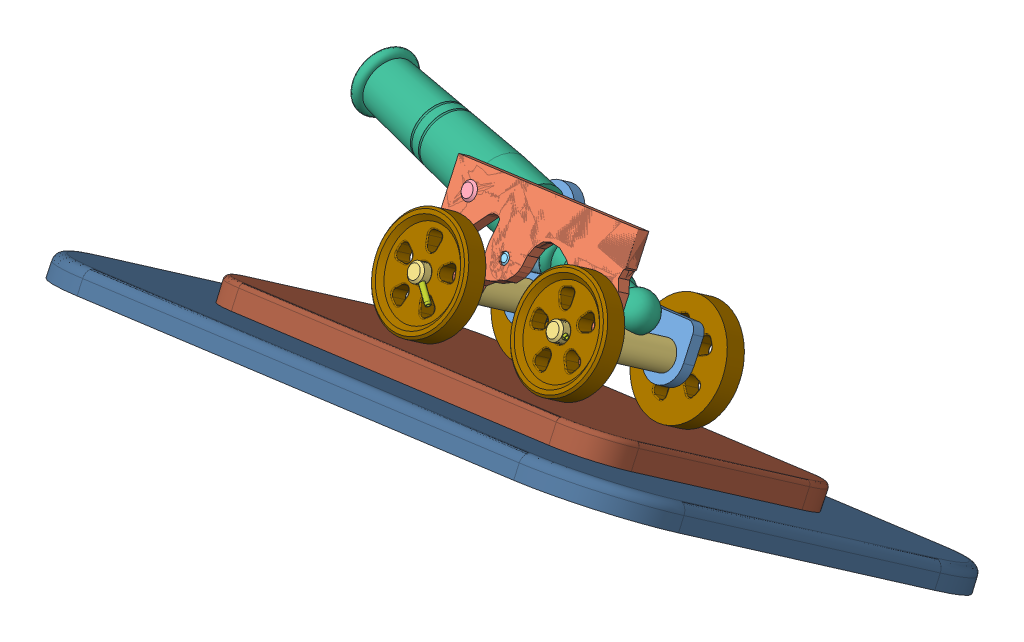
SolidWorks assembly Złożenie1, configuration Domyślna. Lengths in mm.
Overall size (326.22 170.33 191).
18 component instances, 11 part files, 46 mates.
Components (placement in the parent):
- SupportPreMade-1: SupportPreMade [Domyślna] at (-187.0354 39.8991 67.357) x (0.980503 0.186167 0.062894) z (-0.154274 0.531052 0.833177) size (90 50 5.5)
- NewSupport-2: NewSupport [NewSupport] at (-193.0521 60.6102 99.8509) x (0.980503 0.186167 0.062894) z (-0.154274 0.531052 0.833177) size (90.5 50.05 5)
- Axle-1: Axle [Domyślna] at (-176.0562 41.7959 49.5775) x (-0.154274 0.531052 0.833177) z (-0.778757 0.453616 -0.433324) size (70 12 12)
- CannonPin-1: CannonPin [Domyślna] at (-181.5588 72.9675 43.0931) x (-0.154274 0.531052 0.833177) z (0.118877 -0.82717 0.549235) size (46 8.5 8.5)
- SecPin-1: SecPin [Domyślna] at (-155.2532 64.9266 54.2893) x (-0.154274 0.531052 0.833177) z (-0.099202 -0.847337 0.521708) size (44 5 5)
- Axle-2: Axle [Domyślna] at (-107.421 54.8276 53.9801) x (-0.154274 0.531052 0.833177) z (0.987066 0.045635 0.153681) size (70 12 12)
- Barrel-1: Barrel [Domyślna] at (-107.2204 83.0362 78.0454) x (-0.979707 0.026988 -0.198607) z (-0.154274 0.531052 0.833177) size (159.5 26 26)
- spring pin slotted_ai-1: spring pin slotted_ai [SPS 0.0938x0.375] at (-184.286 76.3699 107.032) x (0.778757 -0.453616 0.433324) z (0.47899 -0.016092 -0.877673) size (9.53 2.36 2.36)
- spring pin slotted_ai-2: spring pin slotted_ai [SPS 0.0938x0.375] at (-172.6142 40.8939 53.7903) x (-0.778757 0.453616 -0.433324) z (0.052382 -0.641316 -0.765487) size (9.53 2.36 2.36)
- spring pin slotted_ai-3: spring pin slotted_ai [SPS 0.0938x0.375] at (-112.3569 55.9449 55.3546) x (0.987066 0.045635 0.153681) z (-0.159978 0.218331 0.962673) size (9.53 2.36 2.36)
- spring pin slotted_ai-4: spring pin slotted_ai [SPS 0.0938x0.375] at (-122.3847 90.4632 109.511) x (0.987066 0.045635 0.153681) z (-0.159652 0.366833 0.916485) size (9.53 2.36 2.36)
- WheelBase-1: WheelBase [Domyślna] at (-116.3689 85.6286 102.3043) x (0.925177 0.373607 -0.066821) z (-0.154274 0.531052 0.833177) size (10 10 1)
- Część5^Złożenie1-1: Część5^Złożenie1 [Domyślna] at (-116.5232 86.1597 103.1375) x (0.925177 0.373607 -0.066821) z (-0.154274 0.531052 0.833177) size (44.45 44.45 9) (virtual)
- Część5^Złożenie1-2: Część5^Złożenie1 [Domyślna] at (-109.118 60.6692 63.145) x (-0.886334 -0.447011 0.1208) z (0.154274 -0.531052 -0.833177) size (44.45 44.45 9) (virtual)
- Część5^Złożenie1-3: Część5^Złożenie1 [Domyślna] at (-185.1584 73.1279 98.7349) x (0.397048 -0.738864 0.544457) z (-0.154274 0.531052 0.833177) size (44.45 44.45 9) (virtual)
- Część5^Złożenie1-4: Część5^Złożenie1 [Domyślna] at (-177.7532 47.6374 58.7425) x (-0.838499 0.37567 -0.394705) z (0.154274 -0.531052 -0.833177) size (44.45 44.45 9) (virtual)
- GrassBase-1: GrassBase [Domyślna] at (-146.9015 31.063 103.8247) x (0.980503 0.186167 0.062894) z (-0.154274 0.531052 0.833177) size (300 10 200)
- Część1^Złożenie1-1: Część1^Złożenie1 [Domyślna] at (-148.1186 39.3294 98.3305) x (0.980503 0.186167 0.062894) z (-0.121711 0.826635 -0.549419) size (200 120 10) (virtual)
Mates (geometry in assembly coordinates):
- Koncentryczne1: concentric aligned: cylinder of SupportPreMade-1 through (-178.8331 51.3548 64.5747) axis (0.154274 -0.531052 -0.833177) radius 5.25; cylinder of Axle-1 through (-176.0562 41.7959 49.5775) axis (0.154274 -0.531052 -0.833177) radius 3.95
- Wspólnie1: coincident anti-aligned: plane of SupportPreMade-1 through (-182.4845 76.1539 48.0921) normal (-0.154274 0.531052 0.833177); plane of Axle-1 through (-175.1848 55.649 62.5132) normal (0.154274 -0.531052 -0.833177)
- Koncentryczne2: concentric aligned: cylinder of SupportPreMade-1 through (-156.0245 67.5819 58.4552) axis (0.154274 -0.531052 -0.833177) radius 2.5; cylinder of SecPin-1 through (-155.2532 64.9266 54.2893) axis (0.154274 -0.531052 -0.833177) radius 2.5
- Wspólnie2: coincident aligned: plane of SupportPreMade-1 through (-181.7131 73.4986 43.9262) normal (0.154274 -0.531052 -0.833177); plane of SecPin-1 through (-155.2532 64.9266 54.2893) normal (0.154274 -0.531052 -0.833177)
- Koncentryczne5: concentric aligned: cylinder of SupportPreMade-1 through (-110.1979 64.3865 68.9772) axis (0.154274 -0.531052 -0.833177) radius 5.25; cylinder of Axle-2 through (-107.421 54.8276 53.9801) axis (0.154274 -0.531052 -0.833177) radius 6
- Wspólnie3: coincident anti-aligned: plane of SupportPreMade-1 through (-182.4845 76.1539 48.0921) normal (-0.154274 0.531052 0.833177); plane of Axle-2 through (-110.4595 59.3099 72.1646) normal (0.154274 -0.531052 -0.833177)
- Koncentryczne6: concentric aligned: cylinder of NewSupport-2 through (-116.2146 85.0975 101.4711) axis (0.154274 -0.531052 -0.833177) radius 5.25; cylinder of Axle-2 through (-107.421 54.8276 53.9801) axis (0.154274 -0.531052 -0.833177) radius 6
- Koncentryczne7: concentric aligned: cylinder of NewSupport-2 through (-184.8498 72.0658 97.0686) axis (0.154274 -0.531052 -0.833177) radius 5.25; cylinder of Axle-1 through (-176.0562 41.7959 49.5775) axis (0.154274 -0.531052 -0.833177) radius 6
- Koncentryczne8: concentric aligned: cylinder of NewSupport-2 through (-162.0412 88.2929 90.9491) axis (0.154274 -0.531052 -0.833177) radius 2.5; cylinder of SecPin-1 through (-155.2532 64.9266 54.2893) axis (0.154274 -0.531052 -0.833177) radius 2.5
- Wspólnie4: coincident anti-aligned: plane of NewSupport-2 through (-192.6664 59.2825 97.768) normal (0.154274 -0.531052 -0.833177); plane of Axle-1 through (-181.0382 72.989 91.1848) normal (-0.154274 0.531052 0.833177)
- Wspólnie5: coincident aligned: plane of NewSupport-2 through (-193.4378 61.9378 101.9338) normal (-0.154274 0.531052 0.833177); plane of SecPin-1 through (-162.0412 88.2929 90.9491) normal (-0.154274 0.531052 0.833177)
- Koncentryczne9: concentric aligned: cylinder of SupportPreMade-1 through (-182.4845 76.1539 48.0921) axis (0.154274 -0.531052 -0.833177) radius 3.25; cylinder of CannonPin-1 through (-181.5588 72.9675 43.0931) axis (0.154274 -0.531052 -0.833177) radius 4.25
- Wspólnie6: coincident anti-aligned: plane of NewSupport-2 through (-192.6664 59.2825 97.768) normal (0.154274 -0.531052 -0.833177); plane of CannonPin-1 through (-191.408 93.5205 76.1783) normal (-0.154274 0.531052 0.833177)
- Koncentryczne10: concentric anti-aligned: cylinder of CannonPin-1 through (-181.5588 72.9675 43.0931) axis (0.154274 -0.531052 -0.833177) radius 4.25; cylinder of Barrel-1 through (-183.1016 78.2781 51.4248) axis (-0.154274 0.531052 0.833177) radius 4.25
- Symetrycznie1: symmetric aligned: plane of SupportPreMade-1 through (-181.7131 73.4986 43.9262) normal (0.154274 -0.531052 -0.833177); plane of NewSupport-2 through (-193.4378 61.9378 101.9338) normal (-0.154274 0.531052 0.833177); plane of Barrel-1 through (-107.2204 83.0362 78.0454) normal (-0.154274 0.531052 0.833177)
- Ustalone3: in place: plane of ? through (0 0 9.2378) normal (0 0 1); plane of ? through (0 0 9.2378) normal (0 0 1); moOrthogonalPlaneRef_w of ? through (0 0 9.2378) normal (0 0 1); plane of ? through (0 0 9.2378) normal (0 1 0); plane of ? through (0 0 9.2378) normal (0 0 1); plane of ? through (0 0 9.2378) normal (1 0 0); plane of WheelBase-1 through (-116.5232 86.1597 103.1375) normal (-0.154274 0.531052 0.833177); unknown of Część5^Złożenie1-1
- Wspólnie13: coincident aligned: plane of WheelBase-1; plane of Część5^Złożenie1-1
- Wspólnie14: coincident aligned: moOrthogonalPlaneRef_w of WheelBase-1; plane of Część5^Złożenie1-1 through (-116.5232 86.1597 103.1375) normal (-0.346766 0.760527 -0.548955)
- Wspólnie15: coincident anti-aligned: moOrthogonalPlaneRef_w of WheelBase-1; plane of Część5^Złożenie1-1 through (-116.5232 86.1597 103.1375) normal (0.925177 0.373607 -0.066821)
- Koncentryczne11: concentric aligned: cylinder of Axle-1 through (-176.0562 41.7959 49.5775) axis (0.154274 -0.531052 -0.833177) radius 3.95; cylinder of Część5^Złożenie1-3 through (-186.5468 77.9074 106.2335) axis (0.154274 -0.531052 -0.833177) radius 4
- Odległość1: distance = 2 mm anti-aligned: plane of Część5^Złożenie1-3 through (-185.1584 73.1279 98.7349) normal (0.154274 -0.531052 -0.833177); plane of Axle-1 through (-182.448 74.8928 95.7114) normal (-0.154274 0.531052 0.833177)
- Koncentryczne12: concentric aligned: cylinder of Axle-2 through (-107.421 54.8276 53.9801) axis (0.154274 -0.531052 -0.833177) radius 3.95; cylinder of Część5^Złożenie1-1 through (-117.9116 90.9391 110.6361) axis (0.154274 -0.531052 -0.833177) radius 4
- Odległość2: distance = 2 mm anti-aligned: plane of Axle-2 through (-116.3868 81.7554 103.5695) normal (-0.154274 0.531052 0.833177); plane of Część5^Złożenie1-1 through (-116.5232 86.1597 103.1375) normal (0.154274 -0.531052 -0.833177)
- Koncentryczne14: concentric anti-aligned: cylinder of Axle-2 through (-107.421 54.8276 53.9801) axis (0.154274 -0.531052 -0.833177) radius 3.95; cylinder of Część5^Złożenie1-2 through (-107.7296 55.8897 55.6464) axis (-0.154274 0.531052 0.833177) radius 4
- Koncentryczne15: concentric anti-aligned: cylinder of Axle-1 through (-176.0562 41.7959 49.5775) axis (0.154274 -0.531052 -0.833177) radius 3.95; cylinder of Część5^Złożenie1-4 through (-176.3648 42.858 51.2439) axis (-0.154274 0.531052 0.833177) radius 4
- Odległość3: distance = 2 mm anti-aligned: plane of Część5^Złożenie1-4 through (-177.7532 47.6374 58.7425) normal (-0.154274 0.531052 0.833177); plane of Axle-1 through (-175.0215 52.278 58.6909) normal (0.154274 -0.531052 -0.833177)
- Odległość4: distance = 2 mm anti-aligned: plane of Część5^Złożenie1-2 through (-109.118 60.6692 63.145) normal (-0.154274 0.531052 0.833177); plane of Axle-2 through (-109.6445 57.5007 67.4675) normal (0.154274 -0.531052 -0.833177)
- Koncentryczne16: concentric aligned: cylinder of spring pin slotted_ai-1 through (-191.7037 80.6906 102.9046) axis (-0.778757 0.453616 -0.433324) radius 1.1811; cylinder of Axle-1 through (-181.7972 74.9202 108.4169) axis (-0.778757 0.453616 -0.433324) radius 1.2
- Koncentryczne18: concentric anti-aligned: cylinder of Axle-2 through (-123.7569 90.3998 109.2974) axis (0.987066 0.045635 0.153681) radius 1.2; cylinder of spring pin slotted_ai-4 through (-131.7865 90.0285 108.0472) axis (-0.987066 -0.045635 -0.153681) radius 1.1811
- Koncentryczne20: concentric anti-aligned: cylinder of Axle-1 through (-171.7694 40.4018 54.2604) axis (-0.778757 0.453616 -0.433324) radius 1.2; cylinder of spring pin slotted_ai-2 through (-165.1965 36.5732 57.9177) axis (0.778757 -0.453616 0.433324) radius 1.1811
- Koncentryczne22: concentric anti-aligned: cylinder of Axle-2 through (-113.7291 55.8814 55.1409) axis (0.987066 0.045635 0.153681) radius 1.2; cylinder of spring pin slotted_ai-3 through (-121.7587 55.5102 53.8907) axis (-0.987066 -0.045635 -0.153681) radius 1.1811
- Ustalone4: in place: plane of ? through (257.0418 -144.6962 -4.4543) normal (0 1 0); plane of ? through (0 -144.6962 0) normal (0 1 0); plane of ? through (257.0418 -144.6962 -4.4543) normal (0 1 0); plane of ? through (0 -144.6962 0) normal (0 0 -1); plane of ? through (257.0418 -144.6962 -4.4543) normal (0 1 0); plane of ? through (0 -144.6962 0) normal (1 0 0); plane of GrassBase-1 through (-31.0068 27.9447 55.2582) normal (-0.121711 0.826635 -0.549419); unknown of Część1^Złożenie1-1
- Wspólnie7: coincident aligned: plane of GrassBase-1; plane of Część1^Złożenie1-1
- Wspólnie8: coincident aligned: moOrthogonalPlaneRef_w of GrassBase-1; plane of Część1^Złożenie1-1 through (-148.1186 39.3294 98.3305) normal (0.154274 -0.531052 -0.833177)
- Wspólnie9: coincident anti-aligned: moOrthogonalPlaneRef_w of GrassBase-1; plane of Część1^Złożenie1-1 through (-148.1186 39.3294 98.3305) normal (0.980503 0.186167 0.062894)
- Stycznie8: tangent anti-aligned: cylinder of Część5^Złożenie1-3 through (-186.5468 77.9074 106.2335) axis (0.154274 -0.531052 -0.833177) radius 22.225; plane of Część1^Złożenie1-1 through (-64.7245 41.2471 64.5407) normal (-0.121711 0.826635 -0.549419)
- Stycznie9: tangent anti-aligned: cylinder of Część5^Złożenie1-1 through (-117.9116 90.9391 110.6361) axis (0.154274 -0.531052 -0.833177) radius 22.225; plane of Część1^Złożenie1-1 through (-64.7245 41.2471 64.5407) normal (-0.121711 0.826635 -0.549419)
- Szerokość1: width aligned: plane of NewSupport-2 through (-193.4378 61.9378 101.9338) normal (-0.154274 0.531052 0.833177); plane of Część1^Złożenie1-1 through (-181.7131 73.4986 43.9262) normal (0.154274 -0.531052 -0.833177); plane of SupportPreMade-1 through (-237.0324 64.5655 137.7955) normal (-0.154274 0.531052 0.833177); plane of Część1^Złożenie1-1 through (-218.5195 0.8392 37.8142) normal (0.154274 -0.531052 -0.833177)
- Odległość6: distance = 60 mm aligned: plane of SupportPreMade-1 through (-192.2895 74.2922 47.4632) normal (-0.980503 -0.186167 -0.062894); plane of Część1^Złożenie1-1 through (-241.215 7.7369 53.2199) normal (-0.980503 -0.186167 -0.062894)
- Stycznie19: tangent: cylinder of Axle-1 through (-176.0562 41.7959 49.5775) axis (0.154274 -0.531052 -0.833177) radius 3.95; circle of spring pin slotted_ai-1
- Stycznie25: tangent: cylinder of Axle-2 through (-107.421 54.8276 53.9801) axis (0.154274 -0.531052 -0.833177) radius 3.95; circle of spring pin slotted_ai-4
- Zablokuj2: lock: unknown of Axle-2; unknown of spring pin slotted_ai-4
- Stycznie27: tangent: cylinder of Axle-2 through (-107.421 54.8276 53.9801) axis (0.154274 -0.531052 -0.833177) radius 3.95; circle of spring pin slotted_ai-3
- Zablokuj3: lock: unknown of Axle-2; unknown of spring pin slotted_ai-3
- Stycznie29: tangent: cylinder of Axle-1 through (-176.0562 41.7959 49.5775) axis (0.154274 -0.531052 -0.833177) radius 3.95; circle of spring pin slotted_ai-2
- Zablokuj4: lock: unknown of Axle-1; unknown of spring pin slotted_ai-2
